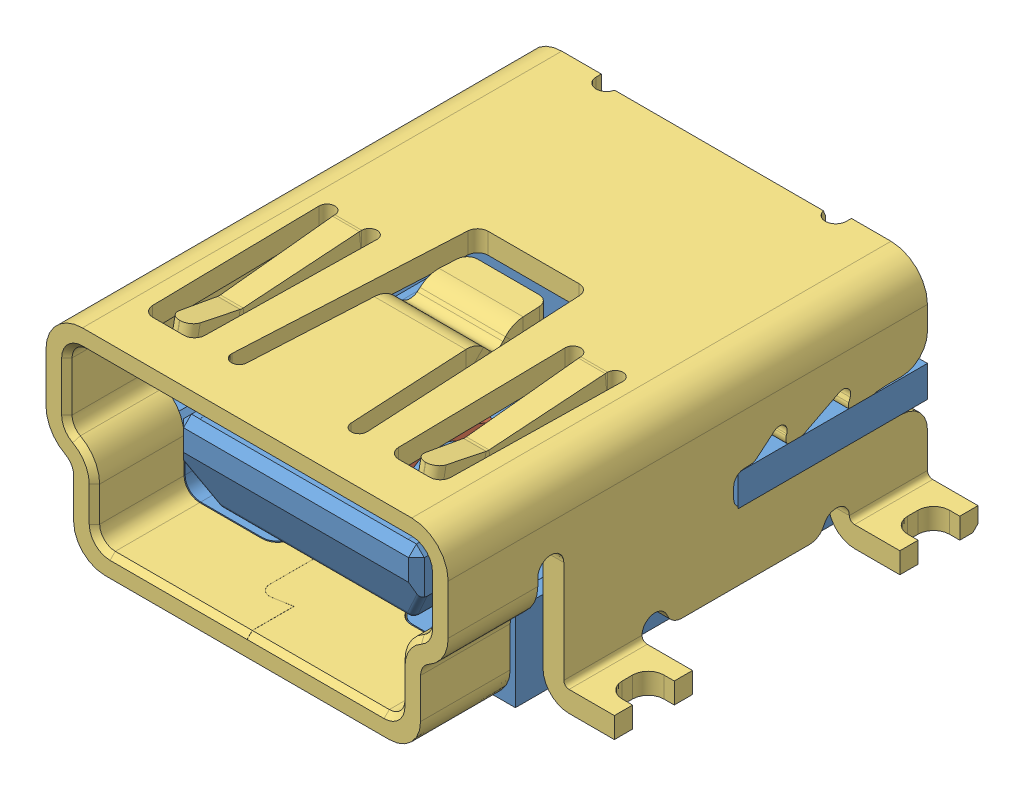
SolidWorks assembly uj2-mbh-2-smt, configuration Default. Lengths in mm.
Overall size (9.66 4.9 9.4).
7 component instances, 3 part files, 0 mates.
Components (placement in the parent):
- internal housing-1: internal housing [Default] at origin size (7.72 4.48 8.26)
- 5_1_Pin-1: 5_1_Pin [Default] at origin size (0.33 3 8.45)
- housing-1: housing [Default] at (0 -0.06 -3.64) size (9.66 3.99 9.2)
- 5_1_Pin-2: 5_1_Pin [Default] at (0.8 0 0) size (0.33 3 8.45)
- 5_1_Pin-3: 5_1_Pin [Default] at (1.6 0 0) size (0.33 3 8.45)
- 5_1_Pin-4: 5_1_Pin [Default] at (2.4 0 0) size (0.33 3 8.45)
- 5_1_Pin-5: 5_1_Pin [Default] at (3.2 0 0) size (0.33 3 8.45)
